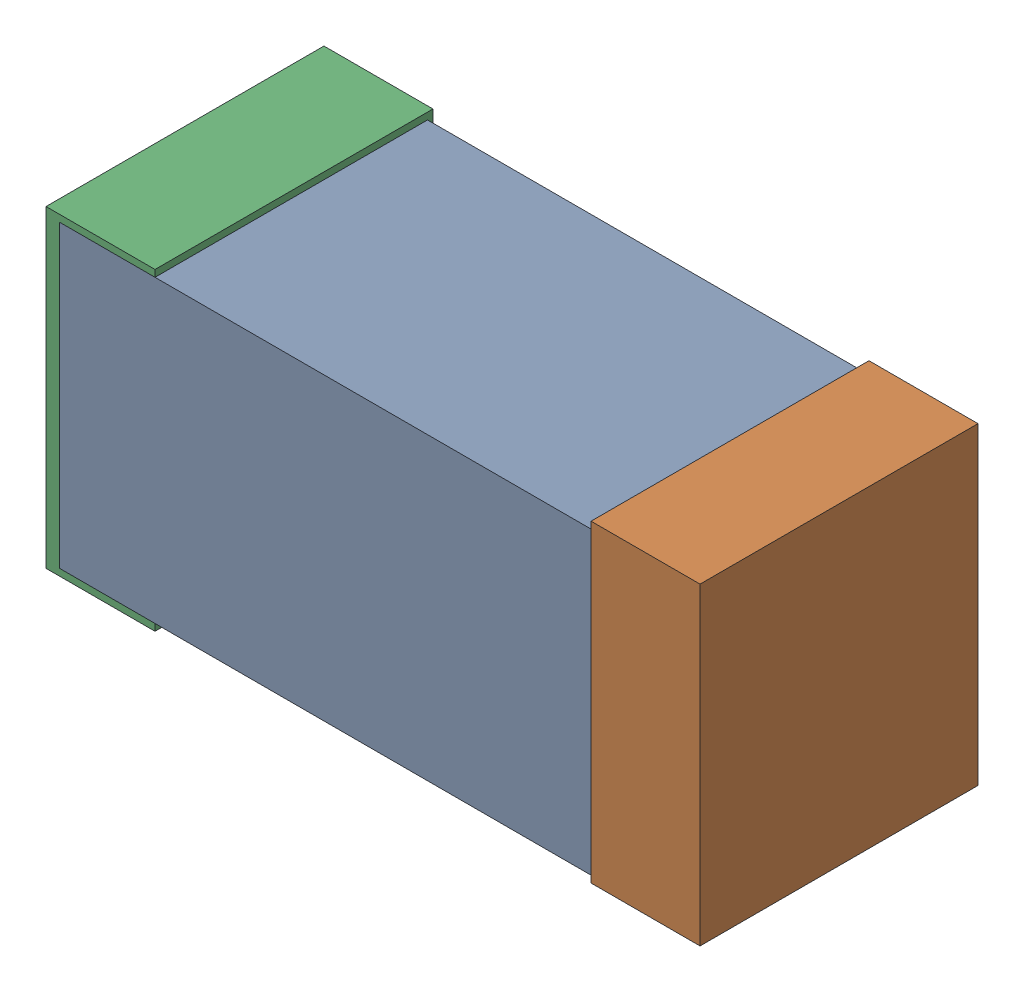
SolidWorks assembly R11, configuration Default. Lengths in mm.
Overall size (1.2 0.58 0.51).
6 component instances, 2 part files, 0 mates.
Components (placement in the parent):
- 384312640-1: 384312640 [Default] at (21.844 27.813 -1.6024) size (1.15 0.55 0.5)
  - Extruded_18-1: Extruded_18 [Default] at origin size (1.15 0.55 0.5)
- 384310976-1: 384310976 [Default] at (22.344 27.813 -1.6124) size (0.2 0.58 0.51)
  - Extruded_19-1: Extruded_19 [Default] at origin size (0.2 0.58 0.51)
- 384310976-2: 384310976 [Default] at (21.344 27.813 -1.6124) size (0.2 0.58 0.51)
  - Extruded_19-1: Extruded_19 [Default] at origin size (0.2 0.58 0.51)
